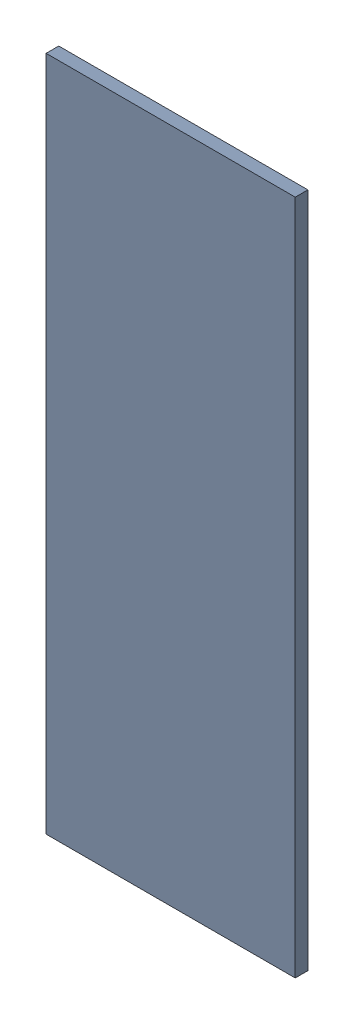
SolidWorks assembly Pad RAK4600-42(17.475mm,31.391mm) on Top Layer, configuration Predeterminado. Lengths in mm.
Overall size (0.7 1.9 0.04).
2 component instances, 1 part files, 0 mates.
Components (placement in the parent):
- Pad RAK4600-42(17.475mm,31.391mm) on Top Layer-1-1: Pad RAK4600-42(17.475mm,31.391mm) on Top Layer-1 [Predeterminado] at (-68.317 -44.187 -0.0457) size (0.7 1.9 0.04)
  - Pad RAK4600-42(17.475mm,31.391mm) on Top Layer-Part-1-1: Pad RAK4600-42(17.475mm,31.391mm) on Top Layer-Part-1 [Predeterminado] at origin size (0.7 1.9 0.04)
